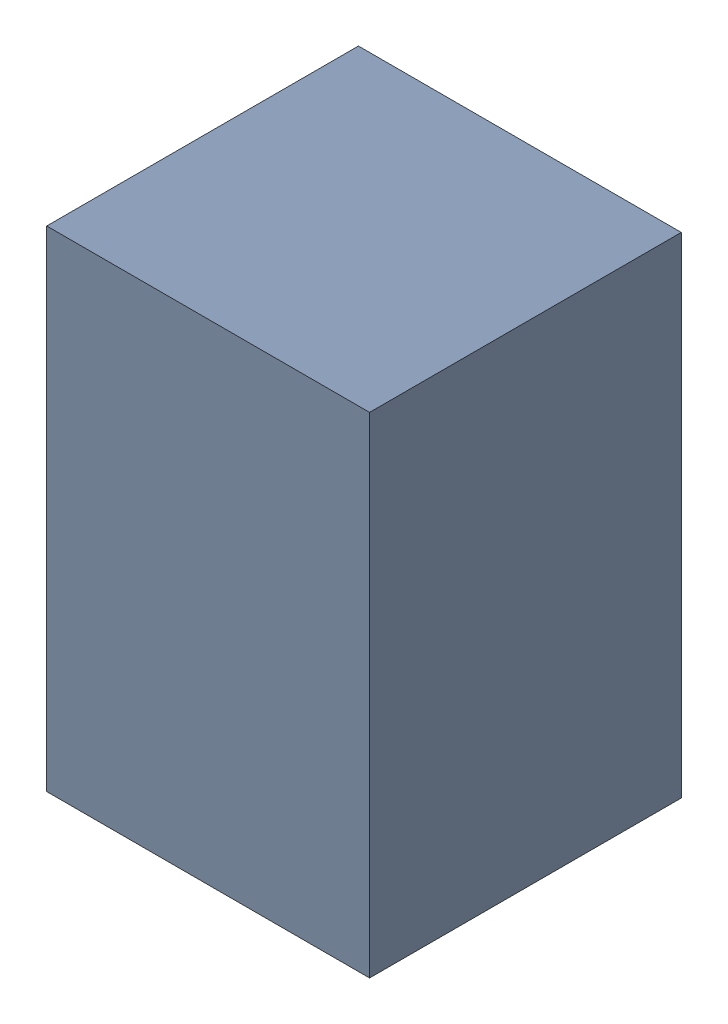
SolidWorks assembly C5, configuration Default. Lengths in mm.
Overall size (1.45 2.2 1.4).
2 component instances, 1 part files, 0 mates.
Components (placement in the parent):
- 580501904-1: 580501904 [Default] at (220.726 99.568 0) size (1.45 2.2 1.4)
  - Extruded_6-1: Extruded_6 [Default] at origin size (1.45 2.2 1.4)
